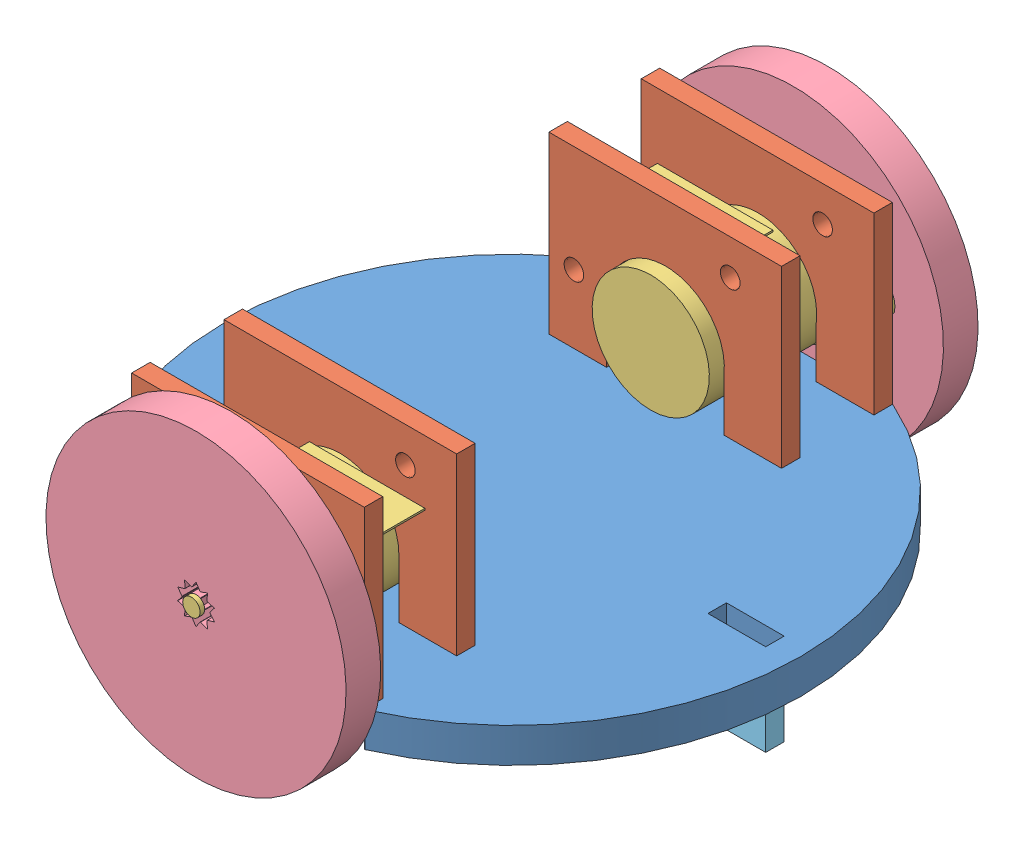
SolidWorks assembly robot, configuration Default. Lengths in mm.
Overall size (50 33.49 55.54).
11 component instances, 5 part files, 15 mates.
Components (placement in the parent):
- base-1: base [Default] at (16.6488 24.1721 39.7283) size (50 3 50)
- motormount-1: motormount [Default] at (16.6238 37.3221 60.9972) size (20.15 18.15 1.6)
- steppermotor-1: steppermotor [Default] at (16.6238 32.2471 62.5972) x (1 0 0) z (0 1 0) size (17.69 15.8 14.16)
- wheel-1: wheel [Default] at (16.6238 32.2471 67.0972) x (-0.93587 0.352345 0) z (-0.352345 -0.93587 0) size (26 3 26)
- caster-1: caster [Default] at (-6.0995 -42.1785 38.9283) size (5 7.92 1.6)
- steppermotor-2: steppermotor [Default] at (16.6721 32.2471 16.8593) x (-1 0 0) z (0 1 0) size (17.69 15.8 14.16)
- wheel-2: wheel [Default] at (16.6238 32.2471 12.3593) x (-0.93587 0.352345 0) z (0.352345 0.93587 0) size (26 3 26)
- motormount-2: motormount [Default] at (16.6238 37.3221 16.8593) size (20.15 18.15 1.6)
- caster-2: caster [Default] at (39.397 -42.1785 40.5283) x (-1 0 0) z (0 0 -1) size (5 7.92 1.6)
- motormount-5: motormount [Default] at (16.6238 37.3221 52.9972) size (20.15 18.15 1.6)
- motormount-6: motormount [Default] at (16.6238 37.3221 24.8593) size (20.15 18.15 1.6)
Mates (geometry in assembly coordinates):
- Coincident1: coincident anti-aligned: plane of motormount-1 through (16.6238 32.2471 62.5972) normal (0 0 1); plane of steppermotor-1 through (16.7128 32.1199 62.5972) normal (0 0 -1)
- Concentric1: concentric anti-aligned: cylinder of motormount-1 through (16.6238 32.2471 62.5972) axis (0 0 -1) radius 5.075; cylinder of steppermotor-1 through (16.6238 32.2471 51.6972) axis (0 0 1) radius 5.075
- Coincident2: coincident aligned: plane of base-1 through (16.6488 24.1721 39.7283) normal (0 -1 0); plane of motormount-1 through (6.5488 24.1721 62.5972) normal (0 -1 0)
- Coincident3: coincident anti-aligned: plane of steppermotor-1 through (16.6238 32.2471 64.0972) normal (0 0 1); plane of wheel-1 through (16.6238 32.2471 64.0972) normal (0 0 -1)
- Coincident4: coincident: line of base-1 through (6.5488 27.1721 62.5972) axis (0 -1 0); plane of motormount-1 through (6.5488 42.3221 62.5972) normal (-1 0 0)
- Coincident5: coincident aligned: plane of base-1 through (16.6488 24.1721 39.7283) normal (0 -1 0); plane of motormount-1 through (6.5488 24.1721 62.5972) normal (0 -1 0)
- Distance1: distance = 0 mm aligned: plane of base-1 through (26.7488 27.1721 62.5972) normal (0 0 1); plane of motormount-1 through (16.6238 32.2471 62.5972) normal (0 0 1)
- Coincident7: coincident aligned: plane of base-1 through (16.6488 27.1721 39.7283) normal (0 1 0); plane of caster-1 through (-6.0995 27.1721 40.5283) normal (0 1 0)
- Coincident9: coincident: line of caster-1 through (-6.0995 27.1721 39.7283) axis (1 0 0); plane of assembly
- Distance2: distance = 18 mm: line of caster-1 through (-1.0995 27.1721 40.5283) axis (0 0 -1); line of base-1 through (16.6488 24.1721 14.7283) axis (0 0 1)
- Concentric4: concentric anti-aligned: circle of steppermotor-1; circle of wheel-1
- Concentric6: concentric anti-aligned: cylinder of steppermotor-1 through (16.6238 32.2471 51.6972) axis (0 0 1) radius 5.075; cylinder of motormount-5 through (16.6238 32.2471 54.5972) axis (0 0 -1) radius 5.075
- Coincident19: coincident aligned: plane of base-1 through (16.6488 24.1721 39.7283) normal (0 -1 0); plane of motormount-5 through (6.5488 24.1721 54.5972) normal (0 -1 0)
- Coincident21: coincident aligned: plane of base-1 through (16.6488 24.1721 39.7283) normal (0 -1 0); plane of motormount-5 through (6.5488 24.1721 54.5972) normal (0 -1 0)
- Distance11: distance = 8 mm aligned: plane of motormount-5 through (16.6238 32.2471 54.5972) normal (0 0 1); plane of motormount-1 through (16.6238 32.2471 62.5972) normal (0 0 1)
